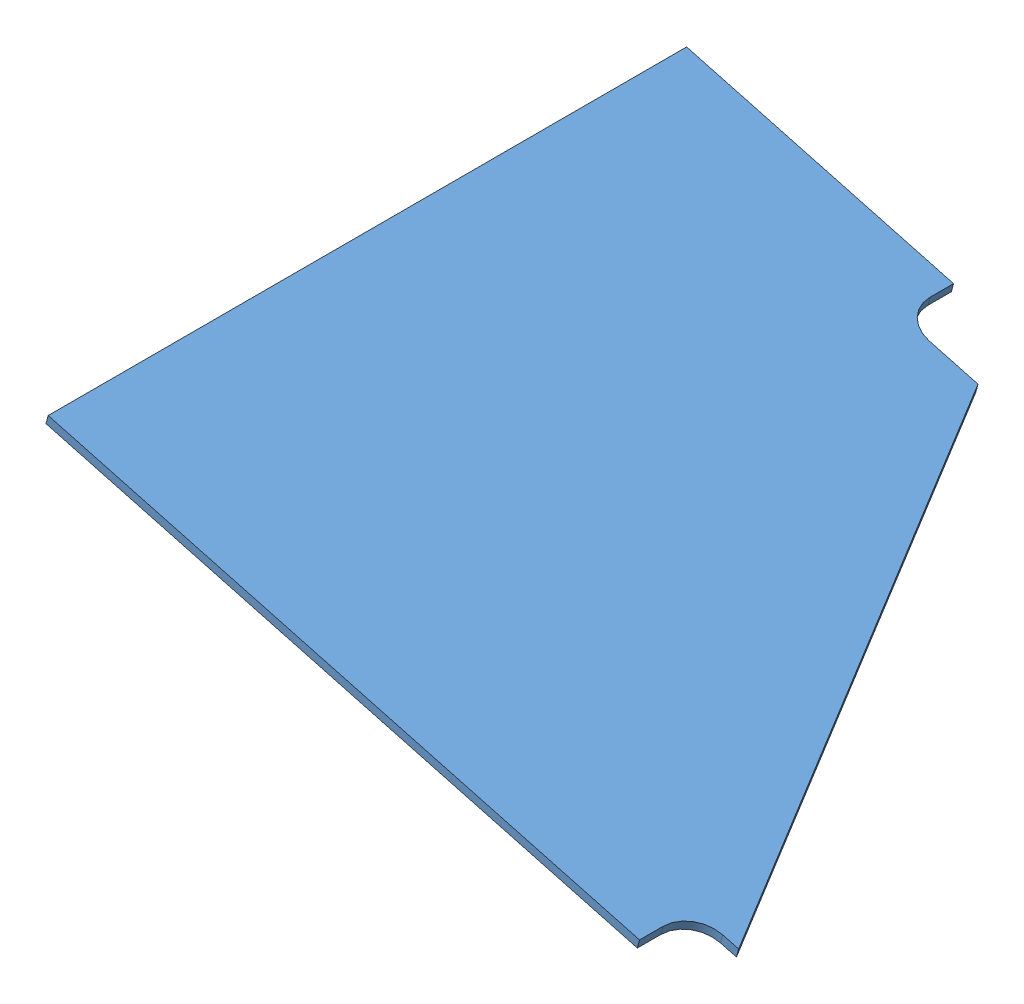
SolidWorks assembly GE-19180, configuration Default. Lengths in mm.
Overall size (481.38 134.68 481.12).
3 component instances, 3 part files, 6 mates.
Components (placement in the parent):
- GE-19115-1: GE-19115 [Default] at origin size (481.38 134.68 481.12)
- Loop_1_14-1: Loop_1_14 [Default] at (30.2573 -9.7509 -9.525) x (0.965926 -0.258819 0) z (0 0 1) size (355.6 1.59 25.4)
- Loop_1_6-1: Loop_1_6 [Default] at (11.8564 -4.8204 -452.5434) x (0.965926 -0.258819 0) z (0 0 1) size (152.4 1.59 25.4)
Mates (geometry in assembly coordinates):
- Coincident7: coincident: plane of GE-19115-1 through (0 0 0) normal (-0.258819 -0.965926 0); plane of Loop_1_14-1 through (30.6681 -8.2175 -9.525) normal (0.258819 0.965926 0)
- Distance5: distance = 6.35 mm: plane of GE-19115-1 through (-32.3131 -120.594 -3.175) normal (0 0 1); plane of Loop_1_14-1 through (30.6681 -8.2175 -9.525) normal (0 0 1)
- Distance6: distance = 31.75 mm: plane of GE-19115-1 through (1.6435 6.1336 -487.4684) normal (-0.965926 0.258819 0); plane of Loop_1_14-1 through (30.6681 -8.2175 -9.525) normal (-0.965926 0.258819 0)
- Coincident10: coincident: plane of GE-19115-1 through (0 0 0) normal (-0.258819 -0.965926 0); plane of ? through (30.6681 -8.2175 -452.5434) normal (0.258819 0.965926 0)
- Distance7: distance = 12.7 mm: plane of GE-19115-1 through (1.6435 6.1336 -487.4684) normal (-0.965926 0.258819 0); plane of Loop_1_6-1 through (12.2673 -3.287 -452.5434) normal (-0.965926 0.258819 0)
- Distance8: distance = 6.35 mm: plane of GE-19115-1 through (-32.3131 -120.594 -484.2934) normal (0 0 -1); plane of Loop_1_6-1 through (12.2673 -3.287 -477.9434) normal (0 0 -1)
